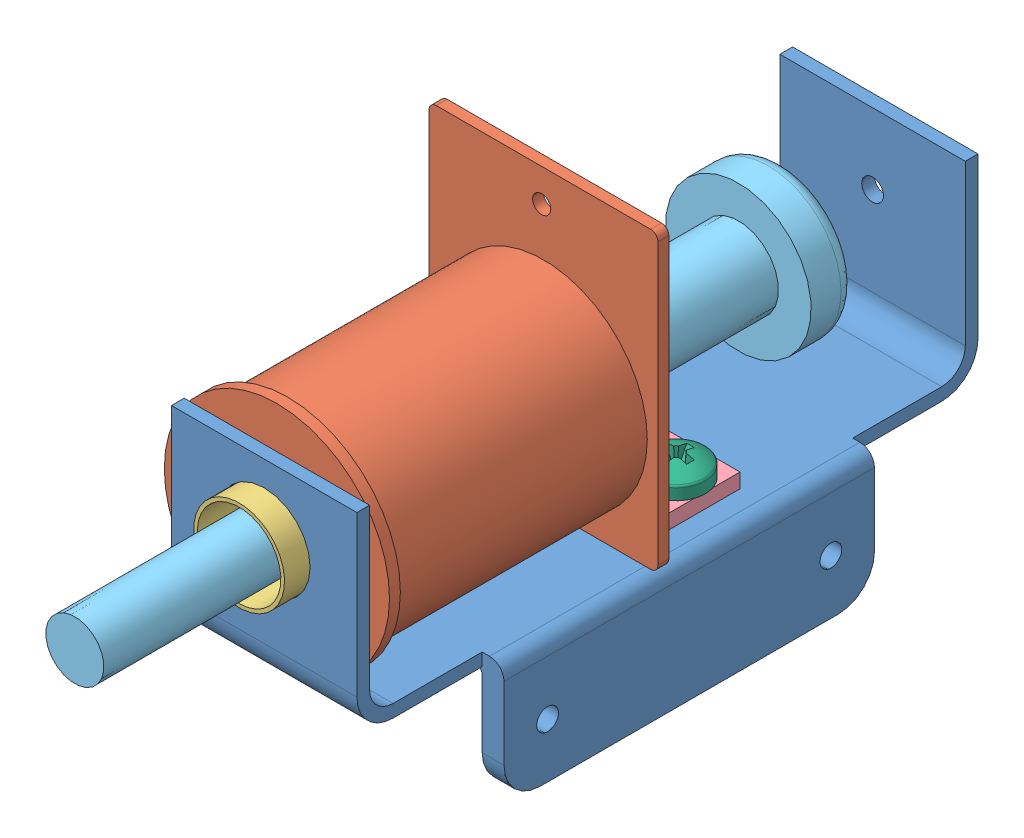
SolidWorks assembly Assemblage Renvoi bille, configuration Défaut. Lengths in mm.
Overall size (31.51 57.79 111.57).
7 component instances, 6 part files, 13 mates.
Components (placement in the parent):
- Platine renvoie bille-1: Platine renvoie bille [Défaut] at (-81.8044 8.8618 42.75) size (28.52 42.25 85.5)
- Bobine Bumpers-1: Bobine Bumpers [Défaut] at (-69.0444 26.1118 4.3) size (31.5 40.79 38.2)
- Fourreau-1: Fourreau [Défaut] at (-69.0444 26.1118 46.2) x (-0.965165 -0.261642 0) z (0 0 -1) size (15.69 15.69 43.9)
- Support Bobine-1: Support Bobine [Défaut] at (-80.0944 10.6118 2.3) size (22.1 25.5 14)
- Plongeur Renvoi bille-1: Plongeur Renvoi bille [Défaut] at (-69.0444 26.1118 68.8168) x (0.991315 -0.131512 0) z (0 0 1) size (20.06 20.06 97.44)
- pan head cross recess screw_iso-2: pan head cross recess screw_iso [ISO 7045 - M4 x 8 - Z --- 8N] at (-61.7944 15.7118 -6.7) x (0 -1 0) z (0 0 1) size (11.02 8 8)
- pan head cross recess screw_iso-3: pan head cross recess screw_iso [ISO 7045 - M4 x 8 - Z --- 8N] at (-76.2944 15.7118 -6.7) x (0 -1 0) z (0 0 1) size (11.02 8 8)
Mates (geometry in assembly coordinates):
- Coaxiale1: concentric aligned: cylinder of Platine renvoie bille-1 through (-69.0444 26.1118 23.1102) axis (0 0 1) radius 6.325; cylinder of Bobine Bumpers-1 through (-69.0444 26.1118 2.8) axis (0 0 1) radius 6.385
- Coaxiale2: concentric aligned: circle of Bobine Bumpers-1; cylinder of Fourreau-1 through (-69.0444 26.1118 2.8) axis (0 0 1) radius 6.25
- Coïncidente2: coincident aligned: plane of Bobine Bumpers-1 through (-54.2944 50.3968 2.8) normal (0 0 -1); circle of Fourreau-1
- Coïncidente3: coincident anti-aligned: plane of Platine renvoie bille-1 through (-56.2844 35.8618 41) normal (0 0 -1); plane of Bobine Bumpers-1 through (-69.0444 26.1118 41) normal (0 0 1)
- Parallèle1: parallel anti-aligned: plane of Platine renvoie bille-1 through (-56.2844 10.6118 37.75) normal (0 1 0); plane of Bobine Bumpers-1 through (-54.2944 10.8568 2.8) normal (0 -1 0)
- Coïncidente6: coincident anti-aligned: plane of Fourreau-1 through (-69.0444 26.1118 2.3) normal (0 0 -1); plane of Support Bobine-1 through (-57.9944 36.1118 2.3) normal (0 0 1)
- Coaxiale5: concentric anti-aligned: cylinder of Fourreau-1 through (-69.0444 26.1118 2.8) axis (0 0 1) radius 5.75; cylinder of Support Bobine-1 through (-69.0444 26.1118 2.3) axis (0 0 -1) radius 6.25
- Coïncidente7: coincident anti-aligned: plane of Platine renvoie bille-1 through (-56.2844 10.6118 37.75) normal (0 1 0); plane of Support Bobine-1 through (-57.9944 10.6118 -0.7) normal (0 -1 0)
- Coaxiale6: concentric aligned: cylinder of Fourreau-1 through (-69.0444 26.1118 2.8) axis (0 0 1) radius 5.75; cylinder of Plongeur Renvoi bille-1 through (-69.0444 26.1118 68.8168) axis (0 0 1) radius 5.53
- Coaxiale7: concentric aligned: cylinder of Support Bobine-1 through (-61.7944 10.6118 -6.7) axis (0 1 0) radius 2; cylinder of pan head cross recess screw_iso-2 through (-61.7944 41.1118 -6.7) axis (0 1 0) radius 4
- Coïncidente8: coincident anti-aligned: plane of Support Bobine-1 through (-57.9944 12.6118 -1.2) normal (0 1 0); plane of pan head cross recess screw_iso-2 through (-59.7944 12.6118 -6.7) normal (0 -1 0)
- Coaxiale8: concentric aligned: cylinder of Support Bobine-1 through (-76.2944 10.6118 -6.7) axis (0 1 0) radius 2; cylinder of pan head cross recess screw_iso-3 through (-76.2944 41.1118 -6.7) axis (0 1 0) radius 4
- Coïncidente9: coincident anti-aligned: plane of Support Bobine-1 through (-57.9944 12.6118 -1.2) normal (0 1 0); plane of pan head cross recess screw_iso-3 through (-74.2944 12.6118 -6.7) normal (0 -1 0)
